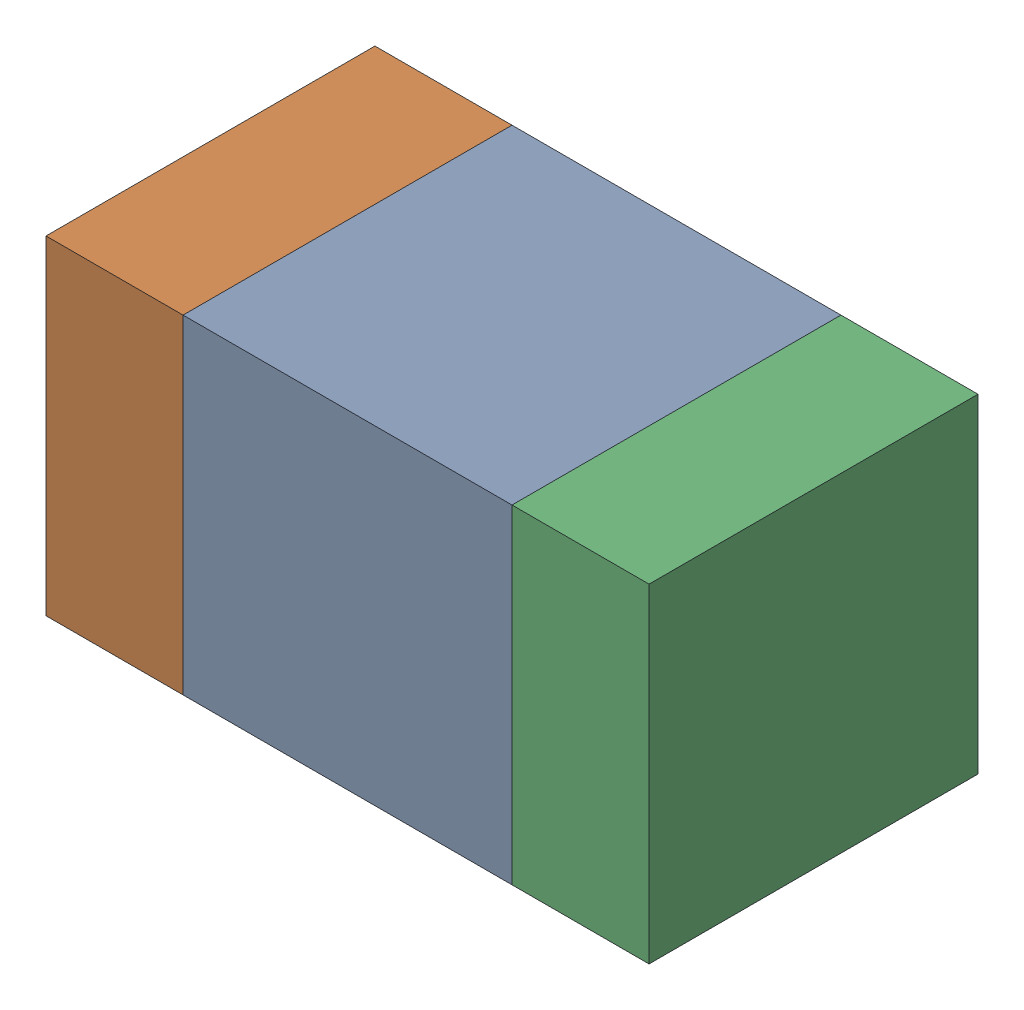
SolidWorks assembly C320_1PCB, configuration Default. Lengths in mm.
Overall size (1.1 0.6 0.6).
6 component instances, 2 part files, 0 mates.
Components (placement in the parent):
- 761606048-1: 761606048 [Default] at (132.9343 120.05 -2.2638) size (0.6 0.6 0.6)
  - Extruded_9-1: Extruded_9 [Default] at origin size (0.6 0.6 0.6)
- 854785160-1: 854785160 [Default] at (132.5093 120.05 -2.2638) size (0.25 0.6 0.6)
  - Extruded_19-1: Extruded_19 [Default] at origin size (0.25 0.6 0.6)
- 854785160-2: 854785160 [Default] at (133.3593 120.05 -2.2638) size (0.25 0.6 0.6)
  - Extruded_19-1: Extruded_19 [Default] at origin size (0.25 0.6 0.6)
